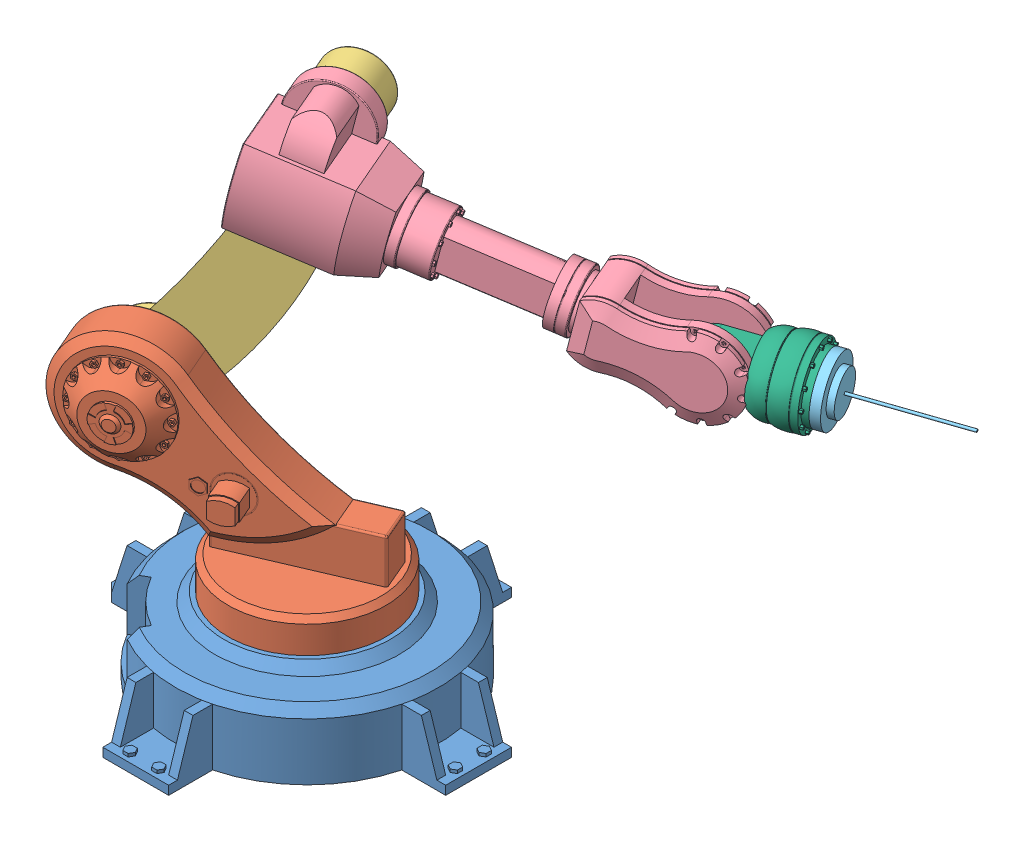
SolidWorks assembly Robotic Arm Model, configuration Default. Lengths in mm.
Overall size (819.62 609.72 474.04).
7 component instances, 6 part files, 8 mates.
Components (placement in the parent):
- Part1-1: Part1 [Default] at (57.0757 143.492 351.8007) size (390.47 105 390.47)
- Part2-1: Part2 [Default] at (57.0757 228.492 351.8007) x (0.91883 0 -0.394654) z (0.394654 0 0.91883) size (308.5 228.5 180)
- Part3-1: Part3 [Default] at (-88.6419 388.492 392.6223) x (-0.444764 -0.875038 0.191034) z (0.804011 -0.484055 -0.345338) size (442.5 70.04 130.16)
- l4-1: l4 [Default] at (298.0597 598.5274 278.7671) x (0.394654 0 0.91883) z (0.897861 -0.212418 -0.385648) size (97.61 133.28 456.17)
- Assem2-1: Assem2 [Default] at (491.3167 572.6481 197.2576) x (-0.232636 -0.883025 -0.407611) z (0.917186 -0.059786 -0.393948) size (115.01 115.01 250)
  - endb^Assem2-1: endb^Assem2 [Default] at (4.5097 -0.8214 0.7246) size (70 70 132) (virtual)
  - enda-1: enda [Default] at (4.5097 -0.8214 -55.2754) x (0.466336 0.884608 0) z (-0.884608 0.466336 0) size (85.14 128 85.14)
Mates (geometry in assembly coordinates):
- Coincident1: coincident anti-aligned: plane of Part1-1 through (57.0757 248.492 351.8007) normal (0 1 0); plane of Part2-1 through (57.0757 248.492 351.8007) normal (0 -1 0)
- Coincident2: coincident aligned: cylinder of Part1-1 through (57.0757 248.492 351.8007) axis (0 -1 0) radius 15; circle of Part2-1
- Coincident3: coincident anti-aligned: plane of Part2-1 through (-80.7488 388.492 410.9989) normal (-0.394654 0 -0.91883); plane of Part3-1 through (-80.7488 388.492 410.9989) normal (0.394654 0 0.91883)
- Concentric1: concentric aligned: cylinder of Part2-1 through (-80.7488 388.492 410.9989) axis (-0.394654 0 -0.91883) radius 15; cylinder of Part3-1 through (-80.7488 388.492 410.9989) axis (-0.394654 0 -0.91883) radius 15
- Coincident4: coincident anti-aligned: plane of Part3-1 through (74.9185 694.7552 344.1369) normal (0.394654 0 0.91883); plane of l4-1 through (74.9185 694.7552 344.1369) normal (-0.394654 0 -0.91883)
- Concentric2: concentric aligned: cylinder of Part3-1 through (74.9185 694.7552 344.1369) axis (-0.394654 0 -0.91883) radius 15; cylinder of l4-1 through (74.9185 694.7552 344.1369) axis (-0.394654 0 -0.91883) radius 15
- Concentric5: concentric aligned: cylinder of l4-1 through (412.1667 574.0993 259.6854) axis (-0.394654 0 -0.91883) radius 15; cylinder of Assem2-1/enda-1 through (412.1667 574.0993 259.6854) axis (-0.394654 0 -0.91883) radius 15
- Coincident10: coincident anti-aligned: plane of l4-1 through (412.1667 574.0993 259.6854) normal (-0.394654 0 -0.91883); plane of Assem2-1/enda-1 through (412.1667 574.0993 259.6854) normal (0.394654 0 0.91883)
